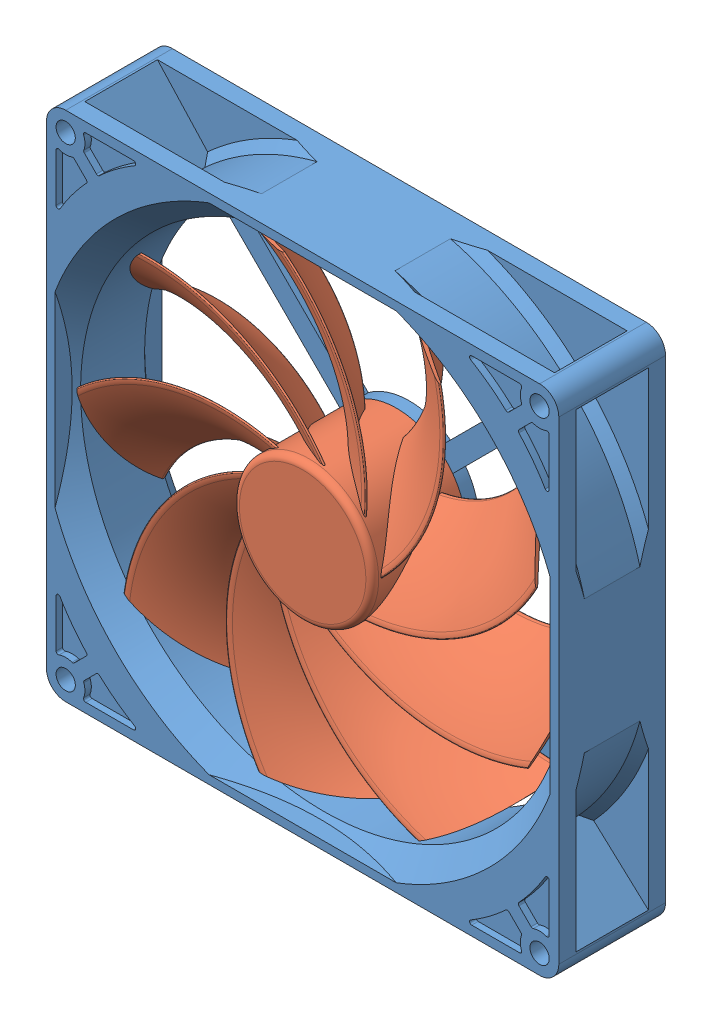
SolidWorks assembly PC FAN, configuration Default. Lengths in mm.
Overall size (160.61 160.57 33.39).
2 component instances, 2 part files, 2 mates.
Components (placement in the parent):
- CPU Fan with no fan-1: CPU Fan with no fan [Default] at origin size (120 120 33.39)
- FanBlade-1: FanBlade [Default] at (0 0 -9.5) x (-0.969943 0.243332 0) z (0 0 1) size (132.38 132.34 22)
Mates (geometry in assembly coordinates):
- Coincident5: coincident: plane of assembly; plane of CPU Fan with no fan-1 through (0 0 -9.5) normal (0 0 1); plane of FanBlade-1 through (0 0 -9.5) normal (0 0 -1)
- Concentric1: concentric: cylinder of assembly; cylinder of CPU Fan with no fan-1 through (0 0 -9.5) axis (0 0 -1) radius 16.3; cylinder of FanBlade-1 through (0 0 12.5) axis (0 0 -1) radius 16.3
